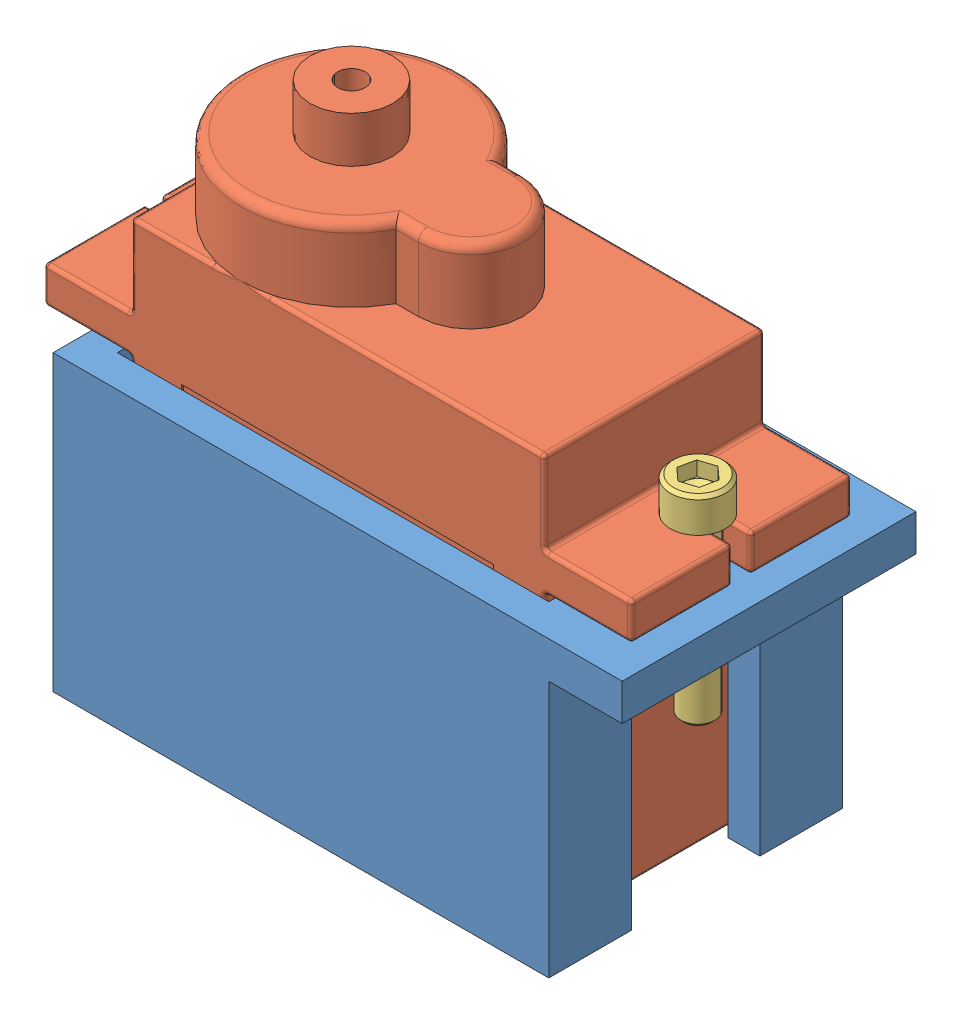
SolidWorks assembly servo with holder, configuration Default. Lengths in mm.
Overall size (33.5 29 16).
4 component instances, 4 part files, 7 mates.
Components (placement in the parent):
- servo holder-1: servo holder [Default] at (13.2606 3.67 20.6898) size (31 16 16)
- Micro Servo SG92R 180-1: Micro Servo SG92R 180 [Valor predeterminado] at (13.2606 19.67 20.6898) size (32 29 12)
- socket head cap screw_ai-1: socket head cap screw_ai [HX-SHCS 0.073-72x0.375x0.375-N] at (26.8856 23.5242 20.6898) x (0 -1 0) z (0.305619 0 0.952154) size (11.38 3 3)
- machine screw nut hex_ai-1: machine screw nut hex_ai [MSHXNUT 0.073-72-S-N] at (26.8856 17.67 20.6898) x (0.999434 0 -0.033627) z (0 1 0) size (3.96 4.58 1.27)
Mates (geometry in assembly coordinates):
- Width1: width anti-aligned: plane of Micro Servo SG92R 180-1 through (13.2606 19.67 14.7898) normal (0 0 -1); plane of Micro Servo SG92R 180-1 through (13.2606 19.67 26.5898) normal (0 0 1); plane of servo holder-1 through (25.0106 3.67 14.4398) normal (0 0 1); plane of servo holder-1 through (25.0106 3.67 26.9398) normal (0 0 -1)
- Width2: width anti-aligned: plane of Micro Servo SG92R 180-1 through (24.5106 3.67 14.6898) normal (1 0 0); plane of Micro Servo SG92R 180-1 through (2.0106 3.67 14.6898) normal (-1 0 0); plane of servo holder-1 through (25.0106 3.67 26.9398) normal (-1 0 0); plane of servo holder-1 through (1.5106 3.67 26.9398) normal (1 0 0)
- Coincident1: coincident anti-aligned: plane of servo holder-1 through (13.2606 19.67 20.6898) normal (0 1 0); plane of Micro Servo SG92R 180-1 through (26.8856 19.67 20.6898) normal (0 -1 0)
- Concentric1: concentric aligned: cylinder of servo holder-1 through (26.8856 3.67 20.6898) axis (0 1 0) radius 1; cylinder of socket head cap screw_ai-1 through (26.8856 55.2742 20.6898) axis (0 1 0) radius 0.9271
- Coincident2: coincident anti-aligned: plane of Micro Servo SG92R 180-1 through (26.8856 21.67 20.6898) normal (0 1 0); plane of socket head cap screw_ai-1 through (28.3125 21.67 20.2318) normal (0 -1 0)
- Concentric2: concentric aligned: cylinder of socket head cap screw_ai-1 through (26.8856 55.2742 20.6898) axis (0 1 0) radius 0.9271; cylinder of machine screw nut hex_ai-1 through (26.8856 16.4 20.6898) axis (0 1 0) radius 0.7556
- Coincident3: coincident anti-aligned: plane of servo holder-1 through (30.7606 17.67 28.6898) normal (0 -1 0); plane of machine screw nut hex_ai-1 through (22.9254 17.67 20.823) normal (0 1 0)
